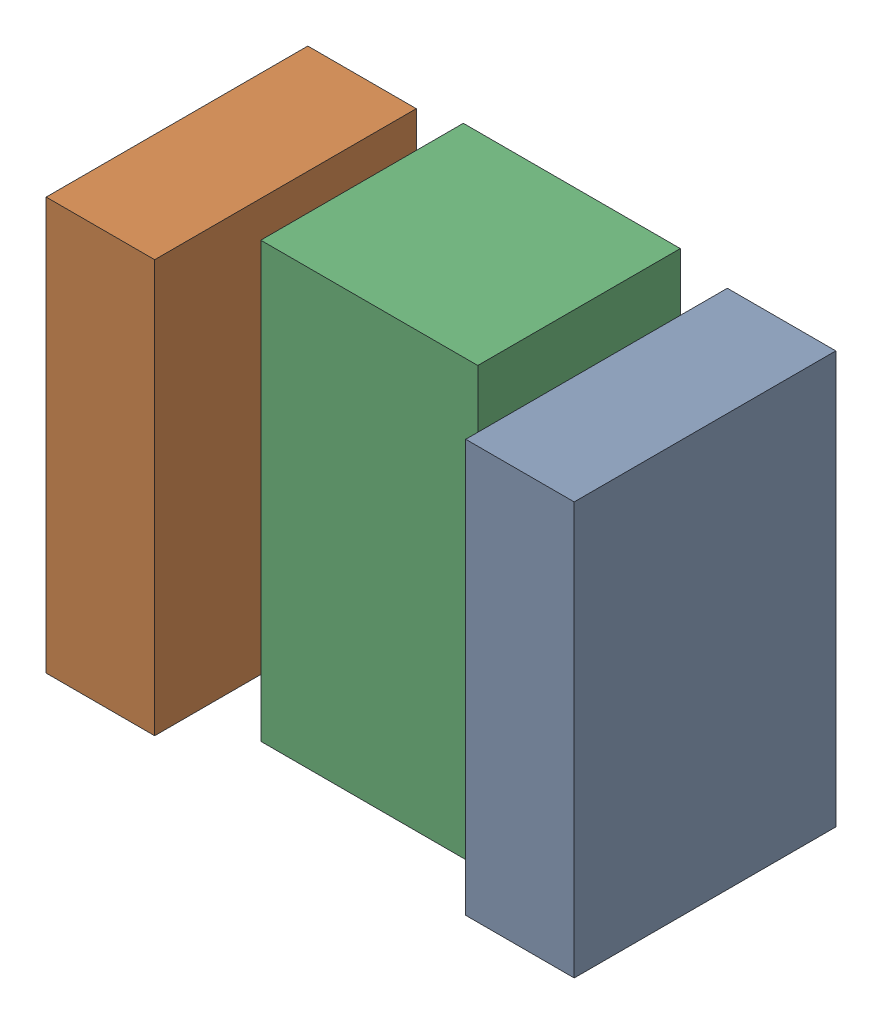
SolidWorks assembly C11_Motor_4Kanaloa_v2.0.0_Motor, configuration Default. Lengths in mm.
Overall size (3.65 3 1.81).
6 component instances, 2 part files, 0 mates.
Components (placement in the parent):
- 334788400-1: 334788400 [Default] at (78.995 81.026 0) size (0.75 2.85 1.81)
  - Extruded_5-1: Extruded_5 [Default] at origin size (0.75 2.85 1.81)
- 334788400-2: 334788400 [Default] at (76.095 81.026 0) size (0.75 2.85 1.81)
  - Extruded_5-1: Extruded_5 [Default] at origin size (0.75 2.85 1.81)
- 334788656-1: 334788656 [Default] at (77.545 81.026 0) size (1.5 3 1.4)
  - Extruded_1-1: Extruded_1 [Default] at origin size (1.5 3 1.4)
